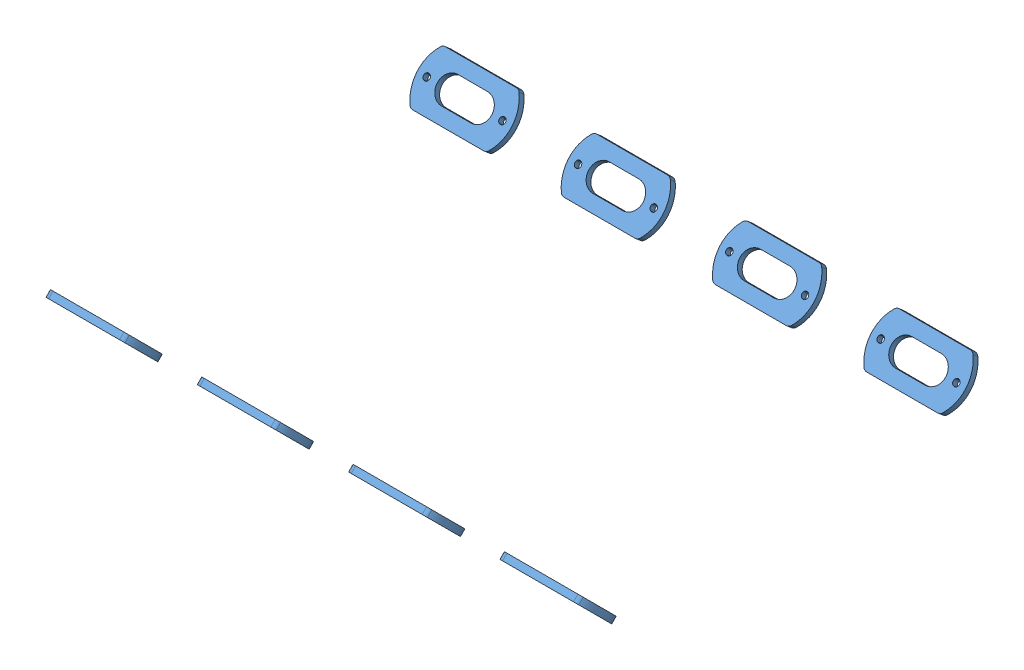
SolidWorks assembly flanges, configuration Default. Lengths in mm.
Overall size (435.48 44.27 318.32).
2 component instances, 1 part files, 0 mates.
Components (placement in the parent):
- AirRail-1: AirRail [Default<As Machined>] at (345.8916 370.7801 -219.481) x (0 0.648313 0.761374) z (-1 0 0) size (5 40 435.28)
- AirRail-2: AirRail [Default<As Machined>] at (-74.3126 360.2061 44.6231) x (0 0.707107 -0.707107) z (1 0 0) size (5 40 435.28)
